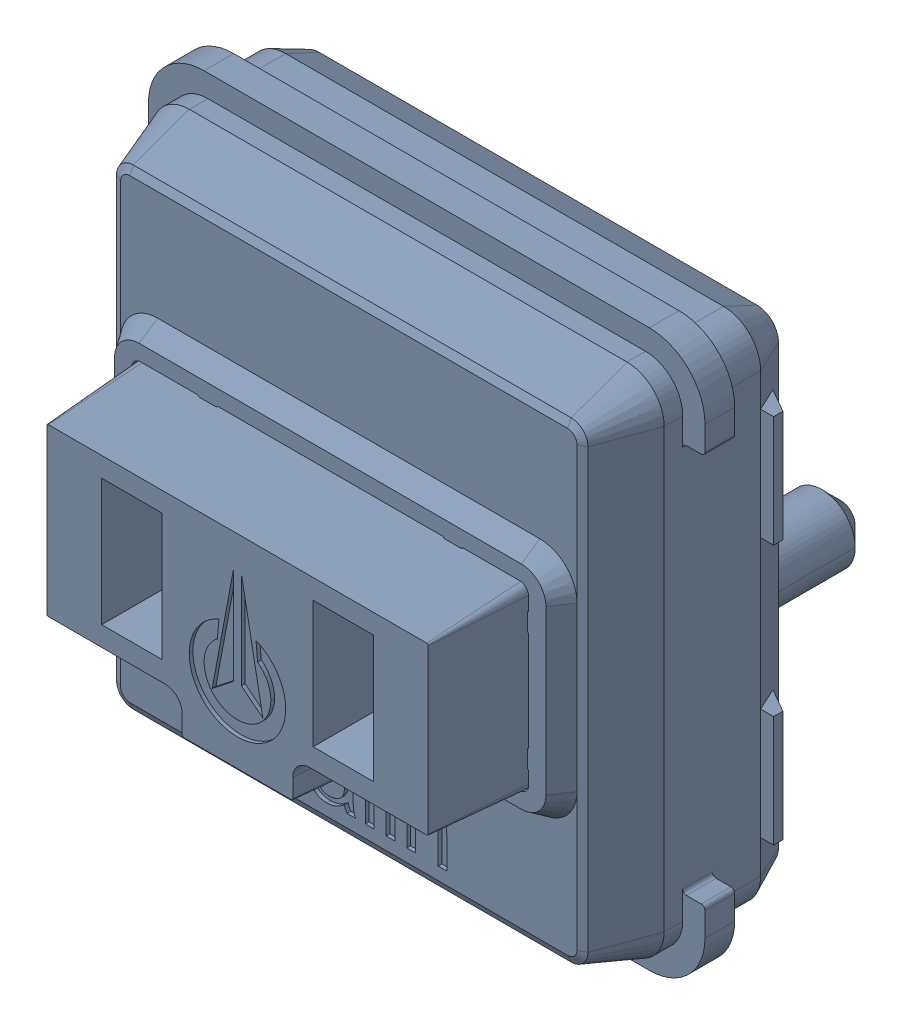
SolidWorks assembly SW4_1.step, configuration Default. Lengths in mm.
Overall size (15 15 11.1).
2 component instances, 2 part files, 0 mates.
Components (placement in the parent):
- Kailh LP Choc Burnt Orange_1.step-11: Kailh LP Choc Burnt Orange_1.step [Default] at (397.1171 226.3933 2.7) x (0 -1 0) z (-1 0 0) size (15 11.1 15)
- WS2812-2020_1.step-11: WS2812-2020_1.step [Default] at (397.2237 231.0345 0.3) x (1 0 0) z (0 -1 0) size (2.2 0.86 2)
